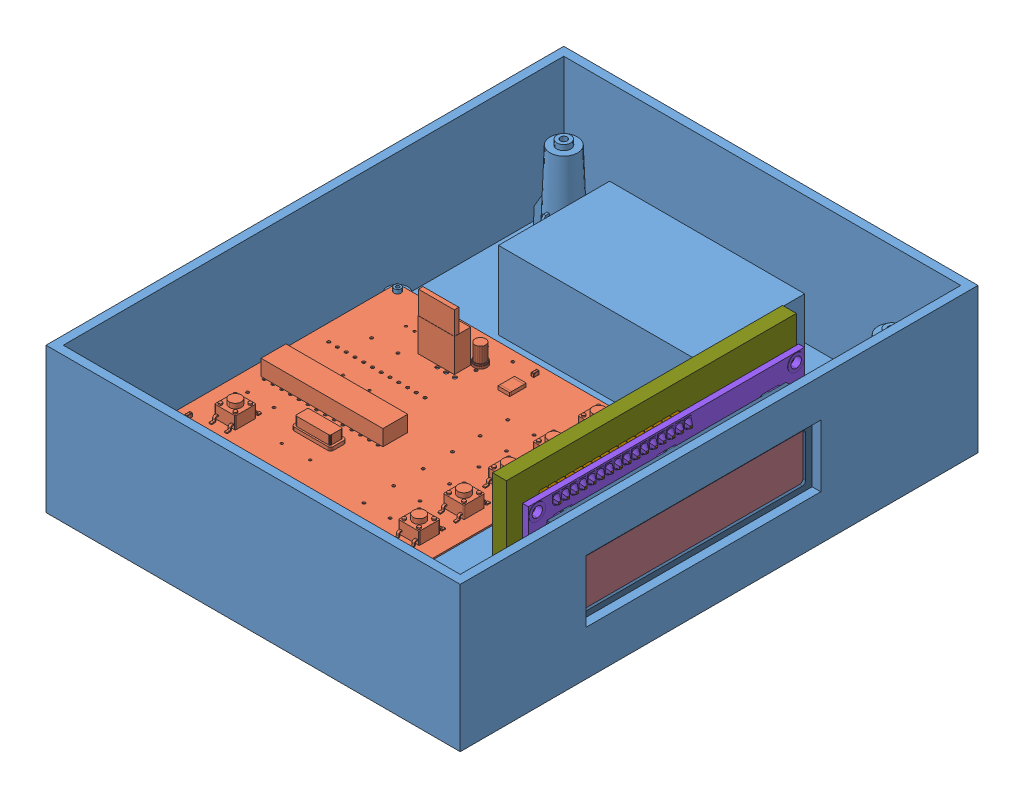
SolidWorks assembly Assem60, configuration Default. Lengths in mm.
Overall size (120.23 50 150.23).
30 component instances, 20 part files, 21 mates.
Components (placement in the parent):
- base1-1: base1 [Default] at (-81.3552 -3.1986 38.3093) size (120.23 45 150.23)
- PCB2.step-1: PCB2.step [Default] at (-19.7622 13.9589 157.0703) x (0 0 -1) z (0 1 0) size (80.65 74.17 20.11)
- Part39^Assem60-1: Part39^Assem60 [Default] at (-81.3552 1.8014 38.3093) x (1 0 0) z (0 1 0) (virtual)
- BatteryHolder_9V_Eyelet_or_Pins-1: BatteryHolder_9V_Eyelet_or_Pins [Default] at (-87.1079 15.8014 -7.8784) x (-1 0 0) z (0 -1 0) size (62.36 30.2 20.5)
  - BatteryHolder_9V_Eyelet_or_Pins.step-1: BatteryHolder_9V_Eyelet_or_Pins.step [Default] at origin size (62.36 30.2 29.4)
    - Body_Housing.step-1: Body_Housing.step [Default] at origin size (54.5 30.2 20.5)
    - Body_Anode.step-1: Body_Anode.step [Default] at (22 -6.35 11.5) size (4.62 9.24 8)
    - Body_Cathode.step-1: Body_Cathode.step [Default] at (22 6.35 11.5) size (4.62 7.3 7.3)
    - Body_Pin.step-1: Body_Pin.step [Default] at origin size (0.8 0.8 19.4) (hidden)
    - Array_Pins.step-1: Array_Pins.step [Default] at origin size (0.8 13.5 19.4) (hidden)
    - Eyelet_bended_Cathode.step-1: Eyelet_bended_Cathode.step [Default] at (26.6 6.35 11.5) x (0 1 0) z (1 0 0) size (5.54 13.94 8.51)
    - Eyelet_bended_Anode.step-1: Eyelet_bended_Anode.step [Default] at (26.6 -6.35 11.5) x (0 1 0) z (1 0 0) size (5.54 13.94 8.51)
- Part9^Assem60-1: Part9^Assem60 [Default] at (-21.3552 -3.1986 38.3093) x (0 0 -1) z (1 0 0) (virtual)
- LCD.STEP-3: LCD.STEP [Default] at (-33.6552 19.8014 42.9691) x (0 0 -1) z (0 -1 0) size (80 18.3 36)
  - pcbboard.STEP-1: pcbboard.STEP [Default] at origin size (80 4.19 36)
  - 16pin_header__.STEP-1: 16pin_header__.STEP [Default] at (-32 0 -15.5) x (0 0 1) z (1 0 0) size (2.54 11.5 40.64)
  - lcd window.STEP-1: lcd window.STEP [Default] at (0 9 1.5) size (71.3 11.8 27.44)
  - backlight.STEP-1: backlight.STEP [Default] at (0 1.7 1.5) x (-1 0 0) z (0 0 -1) size (74.38 2.98 18)
  - conductor.STEP-1: conductor.STEP [Default] at (0 1.7 12.6) size (69.7 5.5 3)
  - conductor.STEP-2: conductor.STEP [Default] at (0 1.7 -9.6) size (69.7 5.5 3)
  - liquid crystal grabcad.STEP-1: liquid crystal grabcad.STEP [Default] at (0 7.9 1.5) size (68.5 2.2 25)
  - smt_resistor222.STEP-1: smt_resistor222.STEP [Default] at (-32.75 0 -5.25) x (0 0 1) z (1 0 0) size (1.8 0.6 4)
  - smt_resistor222.STEP-2: smt_resistor222.STEP [Default] at (-32.75 0 -2.75) x (0 0 1) z (1 0 0) size (1.8 0.6 4)
  - smt_resistor222.STEP-3: smt_resistor222.STEP [Default] at (-32.75 0 -0.25) x (0 0 1) z (1 0 0) size (1.8 0.6 4)
  - smt_resistor222.STEP-4: smt_resistor222.STEP [Default] at (-32.75 0 2.25) x (0 0 1) z (1 0 0) size (1.8 0.6 4)
  - smt_resistor222.STEP-5: smt_resistor222.STEP [Default] at (-32.75 0 4.75) x (0 0 1) z (1 0 0) size (1.8 0.6 4)
  - smt_resistor222.STEP-6: smt_resistor222.STEP [Default] at (-32.75 0 7.25) x (0 0 1) z (1 0 0) size (1.8 0.6 4)
  - smt_resistor101.STEP-1: smt_resistor101.STEP [Default] at (30.25 0 6.1) x (0 0 -1) z (-1 0 0) size (1.8 0.6 5.2)
  - smt_resistor101.STEP-2: smt_resistor101.STEP [Default] at (30.25 0 2.85) x (0 0 -1) z (-1 0 0) size (1.8 0.6 5.2)
- support to LCD-1: support to LCD [Default] at (-35.6552 22.8014 43.6281) x (0 0 1) z (0 -1 0) size (84 4 42)
Mates (geometry in assembly coordinates):
- Concentric1: concentric: cone of base1-1 through (-128.8552 15.0474 23.9743) axis (0 1 0); cylinder of PCB2.step-1 through (-128.8552 13.5474 23.9743) axis (0 -1 0) radius 1
- Concentric2: concentric: cone of base1-1 through (-58.3702 15.0474 23.9743) axis (0 1 0); cylinder of PCB2.step-1 through (-58.3702 13.5474 23.9743) axis (0 -1 0) radius 1
- Coincident1: coincident: plane of base1-1 through (-58.3702 13.5474 23.9743) normal (0 1 0); plane of PCB2.step-1 through (-130.8872 13.5474 102.7143) normal (0 -1 0)
- InPlace1: in place: plane of base1-1 through (-81.3552 -0.1986 38.3093) normal (0 1 0); plane of ? through (0 -0.1986 0) normal (0 1 0); moOrthogonalPlaneRef_w of base1-1 through (-81.3552 -0.1986 38.3093) normal (0 1 0); plane of ? through (0 -0.1986 0) normal (0 0 -1); plane of base1-1 through (-81.3552 -0.1986 38.3093) normal (0 1 0); plane of ? through (0 -0.1986 0) normal (1 0 0); plane of base1-1 through (-81.3552 1.8014 38.3093) normal (0 1 0); unknown of Part39^Assem60-1
- Coincident2: coincident: plane of base1-1; plane of Part39^Assem60-1
- Coincident3: coincident: moOrthogonalPlaneRef_w of base1-1 through (-81.3552 1.8014 38.3093) normal (0 0 -1); plane of Part39^Assem60-1 through (-81.3552 1.8014 38.3093) normal (0 0 -1)
- Coincident4: coincident: moOrthogonalPlaneRef_w of base1-1 through (-81.3552 1.8014 38.3093) normal (-1 0 0); plane of Part39^Assem60-1 through (-81.3552 1.8014 38.3093) normal (1 0 0)
- Coincident14: coincident: plane of base1-1 through (-114.3579 17.3014 -22.9784) normal (1 0 0); plane of BatteryHolder_9V_Eyelet_or_Pins-1/BatteryHolder_9V_Eyelet_or_Pins.step-1/Body_Housing.step-1 through (-114.3579 13.3014 -22.9784) normal (-1 0 0)
- Coincident15: coincident: plane of base1-1 through (-59.8579 17.3014 -22.9784) normal (0 0 1); line of BatteryHolder_9V_Eyelet_or_Pins-1/BatteryHolder_9V_Eyelet_or_Pins.step-1/Body_Housing.step-1 through (-65.3579 15.8014 -22.9784) axis (-1 0 0)
- Coincident16: coincident: plane of base1-1 through (-81.3552 17.3014 38.3093) normal (0 -1 0); plane of BatteryHolder_9V_Eyelet_or_Pins-1/BatteryHolder_9V_Eyelet_or_Pins.step-1/Body_Housing.step-1 through (-112.5503 17.3014 4.414) normal (0 1 0)
- InPlace2: in place: plane of base1-1 through (-21.3552 38.8014 -36.6907) normal (1 0 0); plane of ? through (-21.3552 0 0) normal (1 0 0); plane of base1-1 through (-21.3552 38.8014 -36.6907) normal (1 0 0); plane of ? through (-21.3552 0 0) normal (0 1 0); plane of base1-1 through (-21.3552 38.8014 -36.6907) normal (1 0 0); plane of ? through (-21.3552 0 0) normal (0 0 -1); plane of base1-1 through (-21.3552 38.8014 -36.6907) normal (1 0 0); unknown of Part9^Assem60-1
- Coincident19: coincident: plane of base1-1; plane of Part9^Assem60-1
- Coincident20: coincident: moOrthogonalPlaneRef_w of base1-1 through (-21.3552 -3.1986 38.3093) normal (0 1 0); plane of Part9^Assem60-1 through (-21.3552 -3.1986 38.3093) normal (0 1 0)
- Coincident21: coincident: moOrthogonalPlaneRef_w of base1-1 through (-21.3552 -3.1986 38.3093) normal (0 0 1); plane of Part9^Assem60-1 through (-21.3552 -3.1986 38.3093) normal (0 0 -1)
- Coincident18: coincident: plane of base1-1 through (-81.3552 1.8014 38.3093) normal (0 1 0); plane of LCD.STEP-3/pcbboard.STEP-1 through (-31.9552 1.8014 82.9691) normal (0 -1 0)
- Parallel1: parallel: plane of base1-1 through (-23.8552 1.8014 -34.1907) normal (-1 0 0); plane of LCD.STEP-3/lcd window.STEP-1 through (-23.8552 18.3014 42.9691) normal (1 0 0)
- Coincident20: coincident: plane of base1-1 through (-23.8552 1.8014 -34.1907) normal (-1 0 0); plane of LCD.STEP-3/lcd window.STEP-1 through (-23.8552 18.3014 42.9691) normal (1 0 0)
- Coincident21: coincident: plane of base1-1 through (-81.3552 1.8014 38.3093) normal (0 1 0); plane of support to LCD-1 through (-39.6552 1.8014 1.6281) normal (0 -1 0)
- Coincident22: coincident: plane of LCD.STEP-3/lcd window.STEP-1 through (-35.6552 18.3014 42.9691) normal (-1 0 0); plane of support to LCD-1 through (-35.6552 22.8014 43.6281) normal (1 0 0)
- Lock2: lock: unknown of base1-1; unknown of support to LCD-1
- Lock3: lock: unknown of base1-1; unknown of LCD.STEP-3/pcbboard.STEP-1
